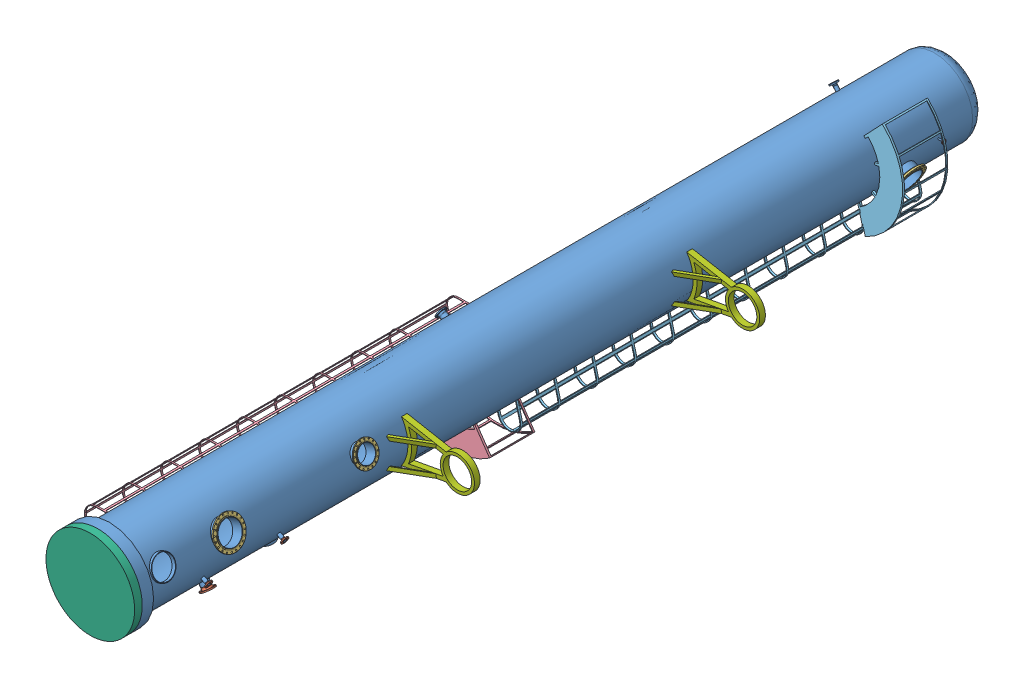
SolidWorks assembly DCAC, configuration Default. Lengths in mm.
Overall size (4447.44 3043.66 22870.94).
19 component instances, 7 part files, 43 mates.
Components (placement in the parent):
- Plast DCAC-1: Plast DCAC [Default] at (2589.7722 3641.4613 -3840.5426) size (2391.8 2365 22670.94)
- welding neck flange-6: welding neck flange [WNeck Flange 150-NPS1] at (3738.2482 3641.4613 -2940.5426) x (0 0 -1) z (1 0 0) size (107.95 107.95 65.38)
- welding neck flange-7: welding neck flange [WNeck Flange 150-NPS1] at (2390.3414 2510.4333 7209.4574) x (0.969846 -0.17101 0.173648) z (-0.173648 -0.984808 0) size (107.95 107.95 65.38)
- welding neck flange-8: welding neck flange [WNeck Flange 150-NPS3] at (2589.7722 2442.9853 17509.4574) x (1 0 0) z (0 -1 0) size (190.5 190.5 79.86)
- welding neck flange-9: welding neck flange [WNeck Flange 150-NPS3] at (1832.2624 2738.6963 16309.4574) x (0.586824 -0.492404 0.642788) z (-0.642788 -0.766044 0) size (190.5 190.5 79.86)
- welding neck flange-10: welding neck flange [WNeck Flange 150-NPS3] at (1832.2624 2738.6963 14309.4574) x (0.586824 -0.492404 0.642788) z (-0.642788 -0.766044 0) size (190.5 190.5 79.86)
- welding neck flange-11: welding neck flange [WNeck Flange 150-NPS3] at (3657.8342 3143.4159 16309.4574) x (0.178606 0.383022 -0.906308) z (0.906308 -0.422618 0) size (190.5 190.5 79.86)
- welding neck flange-12: welding neck flange [WNeck Flange 150-NPS3] at (3657.8342 3143.4159 14309.4574) x (0.178606 0.383022 -0.906308) z (0.906308 -0.422618 0) size (190.5 190.5 79.86)
- welding neck flange-14: welding neck flange [WNeck Flange 150-NPS8] at (3277.1898 2659.7273 15953.4773) x (0.67101 0.469846 -0.573576) z (0.573576 -0.819152 0) size (342.9 342.9 111.61)
- slip on weld flange-1: slip on weld flange [Slip On Flange 150-NPS24] at (3677.3416 3134.3194 -2104.5426) x (0.178606 0.383022 -0.906308) z (0.906308 -0.422618 0) size (812.8 812.8 82.56)
- slip on weld flange-2: slip on weld flange [Slip On Flange 150-NPS24] at (1818.4271 2722.208 7909.4574) x (0.586824 -0.492404 0.642788) z (-0.642788 -0.766044 0) size (812.8 812.8 82.56)
- slip on weld flange-3: slip on weld flange [Slip On Flange 150-NPS18] at (1818.4271 2722.208 6509.4574) x (0.586824 -0.492404 0.642788) z (-0.642788 -0.766044 0) size (635 635 68.34)
- slip on weld flange-4: slip on weld flange [Slip On Flange 150-NPS18] at (3702.3928 4090.9892 12209.4574) x (0.14033 -0.347329 -0.927184) z (0.927184 0.374607 0) size (635 635 68.34)
- slip on weld flange-5: slip on weld flange [Slip On Flange 150-NPS24] at (3702.3928 4090.9892 15795.4574) x (0.14033 -0.347329 -0.927184) z (0.927184 0.374607 0) size (812.8 812.8 82.56)
- DONJA PLATFORMA-1: DONJA PLATFORMA [Default] at (0 0 8779.4574) size (2665.43 2007.97 9540)
- Part8^DCAC-1: Part8^DCAC [Default] at (0 0 -1340.5426) size (1750.85 2897.07 10550)
- TEMELJNA STOPA DCAC^DCAC-1: TEMELJNA STOPA DCAC^DCAC [Default] at (2589.7722 3641.4613 18159.4574) size (2330 2330 200) (virtual)
- Oslonac-1: Oslonac [Default] at origin size (2362.53 1114.42 1084.57)
- Oslonac-2: Oslonac [Default] at (0 0 -7500) size (2362.53 1114.42 1084.57)
Mates (geometry in assembly coordinates):
- Concentric61: concentric anti-aligned: cylinder of Plast DCAC-1 through (4157.4011 3641.4613 -2940.5426) axis (1 0 0) radius 13.4505; cylinder of welding neck flange-6 through (3739.7722 3641.4613 -2940.5426) axis (-1 0 0) radius 24.638
- Coincident51: coincident aligned: plane of Plast DCAC-1 through (3739.7722 3641.4613 -2953.9931) normal (1 0 0); plane of welding neck flange-6 through (3739.7722 3641.4613 -2940.5426) normal (1 0 0)
- Concentric71: concentric anti-aligned: cylinder of Plast DCAC-1 through (2326.5275 2148.5265 7209.4574) axis (-0.173648 -0.984808 0) radius 16.765; cylinder of welding neck flange-7 through (2390.0768 2508.9324 7209.4574) axis (0.173648 0.984808 0) radius 24.638
- Coincident61: coincident aligned: plane of Plast DCAC-1 through (2390.0768 2508.9324 7192.6924) normal (-0.173648 -0.984808 0); plane of welding neck flange-7 through (2390.0768 2508.9324 7209.4574) normal (-0.173648 -0.984808 0)
- Concentric81: concentric anti-aligned: cylinder of Plast DCAC-1 through (2589.7722 1218.4174 17509.4574) axis (0 -1 0) radius 44.45; cylinder of welding neck flange-8 through (2589.7722 2441.4613 17509.4574) axis (0 1 0) radius 53.975
- Coincident71: coincident aligned: plane of Plast DCAC-1 through (2589.7722 2441.4613 17465.0074) normal (0 -1 0); plane of welding neck flange-8 through (2589.7722 2441.4613 17509.4574) normal (0 -1 0)
- Concentric91: concentric aligned: cylinder of Plast DCAC-1 through (2589.7722 3641.4613 16309.4574) axis (0.642788 0.766044 0) radius 38.96; cylinder of welding neck flange-9 through (1831.2828 2737.5289 16309.4574) axis (0.642788 0.766044 0) radius 53.975
- Coincident81: coincident aligned: plane of Plast DCAC-1 through (1831.2828 2737.5289 16265.0074) normal (-0.642788 -0.766044 0); plane of welding neck flange-9 through (1831.2828 2737.5289 16309.4574) normal (-0.642788 -0.766044 0)
- Concentric101: concentric aligned: cylinder of Plast DCAC-1 through (2589.7722 3641.4613 14309.4574) axis (0.642788 0.766044 0) radius 38.96; cylinder of welding neck flange-10 through (1831.2828 2737.5289 14309.4574) axis (0.642788 0.766044 0) radius 53.975
- Coincident91: coincident aligned: plane of Plast DCAC-1 through (1831.2828 2737.5289 14265.0074) normal (-0.642788 -0.766044 0); plane of welding neck flange-10 through (1831.2828 2737.5289 14309.4574) normal (-0.642788 -0.766044 0)
- Concentric111: concentric aligned: cylinder of Plast DCAC-1 through (2589.7722 3641.4613 16309.4574) axis (-0.906308 0.422618 0) radius 44.45; cylinder of welding neck flange-11 through (3659.2154 3142.7718 16309.4574) axis (-0.906308 0.422618 0) radius 53.975
- Coincident101: coincident aligned: plane of Plast DCAC-1 through (3659.2154 3142.7718 16265.0074) normal (0.906308 -0.422618 0); plane of welding neck flange-11 through (3659.2154 3142.7718 16309.4574) normal (0.906308 -0.422618 0)
- Concentric121: concentric aligned: cylinder of Plast DCAC-1 through (2589.7722 3641.4613 14309.4574) axis (-0.906308 0.422618 0) radius 44.45; cylinder of welding neck flange-12 through (3659.2154 3142.7718 14309.4574) axis (-0.906308 0.422618 0) radius 53.975
- Coincident111: coincident aligned: plane of Plast DCAC-1 through (3659.2154 3142.7718 14265.0074) normal (0.906308 -0.422618 0); plane of welding neck flange-12 through (3659.2154 3142.7718 14309.4574) normal (0.906308 -0.422618 0)
- Concentric141: concentric aligned: cylinder of Plast DCAC-1 through (2589.7722 3641.4613 15953.4773) axis (-0.573576 0.819152 0) radius 109.475; cylinder of welding neck flange-14 through (3278.0639 2658.4789 15953.4773) axis (-0.573576 0.819152 0) radius 123.063
- Coincident131: coincident aligned: plane of Plast DCAC-1 through (3278.0639 2658.4789 15844.0023) normal (0.573576 -0.819152 0); plane of welding neck flange-14 through (3278.0639 2658.4789 15953.4773) normal (0.573576 -0.819152 0)
- Concentric161: concentric anti-aligned: cylinder of Plast DCAC-1 through (2589.7722 3641.4613 -2104.5426) axis (-0.906308 0.422618 0) radius 304.8; cylinder of slip on weld flange-1 through (3602.5258 3169.2066 -2104.5426) axis (0.906308 -0.422618 0) radius 331.724
- Coincident151: coincident aligned: plane of Plast DCAC-1 through (3677.3416 3134.3194 -1806.0426) normal (0.906308 -0.422618 0); plane of slip on weld flange-1 through (3677.3416 3134.3194 -2104.5426) normal (0.906308 -0.422618 0)
- Concentric171: concentric aligned: cylinder of Plast DCAC-1 through (600.3885 1270.6061 7909.4574) axis (-0.642788 -0.766044 0) radius 298.45; cylinder of slip on weld flange-2 through (1871.4892 2785.445 7909.4574) axis (-0.642788 -0.766044 0) radius 331.724
- Coincident161: coincident aligned: plane of Plast DCAC-1 through (1818.4271 2722.208 7604.6574) normal (-0.642788 -0.766044 0); plane of slip on weld flange-2 through (1818.4271 2722.208 7909.4574) normal (-0.642788 -0.766044 0)
- Concentric181: concentric anti-aligned: cylinder of Plast DCAC-1 through (2589.7722 3641.4613 6509.4574) axis (0.642788 0.766044 0) radius 222.3; cylinder of slip on weld flange-3 through (1862.3462 2774.5488 6509.4574) axis (-0.642788 -0.766044 0) radius 252.476
- Coincident171: coincident aligned: plane of Plast DCAC-1 through (1818.4271 2722.208 6280.8574) normal (-0.642788 -0.766044 0); plane of slip on weld flange-3 through (1818.4271 2722.208 6509.4574) normal (-0.642788 -0.766044 0)
- Concentric191: concentric anti-aligned: cylinder of Plast DCAC-1 through (2589.7722 3641.4613 12209.4574) axis (-0.927184 -0.374607 0) radius 222.25; cylinder of slip on weld flange-4 through (3639.0421 4065.3939 12209.4574) axis (0.927184 0.374607 0) radius 252.476
- Coincident181: coincident aligned: plane of Plast DCAC-1 through (3702.3928 4090.9892 11980.8574) normal (0.927184 0.374607 0); plane of slip on weld flange-4 through (3702.3928 4090.9892 12209.4574) normal (0.927184 0.374607 0)
- Concentric201: concentric anti-aligned: cylinder of Plast DCAC-1 through (2589.7722 3641.4613 15795.4574) axis (-0.927184 -0.374607 0) radius 304.8; cylinder of slip on weld flange-5 through (3625.8538 4060.0655 15795.4574) axis (0.927184 0.374607 0) radius 331.724
- Coincident191: coincident aligned: plane of Plast DCAC-1 through (3702.3928 4090.9892 15490.6574) normal (0.927184 0.374607 0); plane of slip on weld flange-5 through (3702.3928 4090.9892 15795.4574) normal (0.927184 0.374607 0)
- InPlace1: in place: plane of DONJA PLATFORMA-1 through (0 0 8779.4574) normal (0 0 1); moOrthogonalPlaneRef_w of DONJA PLATFORMA-1 through (0 0 8779.4574) normal (0 1 0); plane of DONJA PLATFORMA-1 through (0 0 8779.4574) normal (1 0 0); unknown of DONJA PLATFORMA-1
- Coincident20: coincident aligned: plane of DONJA PLATFORMA-1; plane of assembly
- Coincident21: coincident aligned: plane of DONJA PLATFORMA-1 through (0 0 8779.4574) normal (0 1 0); moOrthogonalPlaneRef_w of assembly
- Coincident22: coincident anti-aligned: plane of DONJA PLATFORMA-1 through (0 0 8779.4574) normal (1 0 0); moOrthogonalPlaneRef_w of assembly
- InPlace2: in place: plane of Part8^DCAC-1 through (0 0 -1340.5426) normal (0 0 1); plane of Part8^DCAC-1 through (0 0 -1340.5426) normal (0 1 0); plane of Part8^DCAC-1 through (0 0 -1340.5426) normal (1 0 0); unknown of Part8^DCAC-1
- Coincident23: coincident aligned: plane of Part8^DCAC-1; plane of assembly
- Coincident24: coincident aligned: plane of Part8^DCAC-1 through (0 0 -1340.5426) normal (0 1 0); moOrthogonalPlaneRef_w of assembly
- Coincident25: coincident anti-aligned: plane of Part8^DCAC-1 through (0 0 -1340.5426) normal (1 0 0); moOrthogonalPlaneRef_w of assembly
- InPlace3: in place: plane of Plast DCAC-1 through (2589.7722 3641.4613 18159.4574) normal (0 0 1); plane of ? through (0 0 18159.4574) normal (0 0 1); plane of Plast DCAC-1 through (2589.7722 3641.4613 18159.4574) normal (0 0 1); plane of ? through (0 0 18159.4574) normal (0 1 0); plane of Plast DCAC-1 through (2589.7722 3641.4613 18159.4574) normal (0 0 1); plane of ? through (0 0 18159.4574) normal (1 0 0); plane of Plast DCAC-1 through (2589.7722 3641.4613 18159.4574) normal (0 0 1); unknown of TEMELJNA STOPA DCAC^DCAC-1
- Coincident192: coincident aligned: plane of Plast DCAC-1; plane of TEMELJNA STOPA DCAC^DCAC-1
- Coincident193: coincident aligned: moOrthogonalPlaneRef_w of Plast DCAC-1 through (2589.7722 3641.4613 18159.4574) normal (0 1 0); plane of TEMELJNA STOPA DCAC^DCAC-1 through (2589.7722 3641.4613 18159.4574) normal (0 1 0)
- Coincident194: coincident anti-aligned: moOrthogonalPlaneRef_w of Plast DCAC-1 through (2589.7722 3641.4613 18159.4574) normal (-1 0 0); plane of TEMELJNA STOPA DCAC^DCAC-1 through (2589.7722 3641.4613 18159.4574) normal (1 0 0)
- InPlace4: in place: plane of Oslonac-1 through (0 0 0) normal (0 0 1); plane of Oslonac-1 through (0 0 0) normal (0 1 0); plane of Oslonac-1 through (0 0 0) normal (1 0 0); unknown of Oslonac-1
- Coincident192: coincident aligned: plane of Oslonac-1; plane of assembly
- Coincident193: coincident aligned: plane of Oslonac-1; moOrthogonalPlaneRef_w of assembly
- Coincident194: coincident anti-aligned: plane of Oslonac-1 through (0 0 0) normal (1 0 0)
- PLANE1: unknown: plane of Plast DCAC-1 through (2589.7722 3641.4613 18159.4574) normal (0 0 1); sketch_entity of DONJA PLATFORMA-1; unknown of Plast DCAC-1; unknown of Plast DCAC-1; unknown of Plast DCAC-1; unknown of Plast DCAC-1; unknown of Plast DCAC-1
